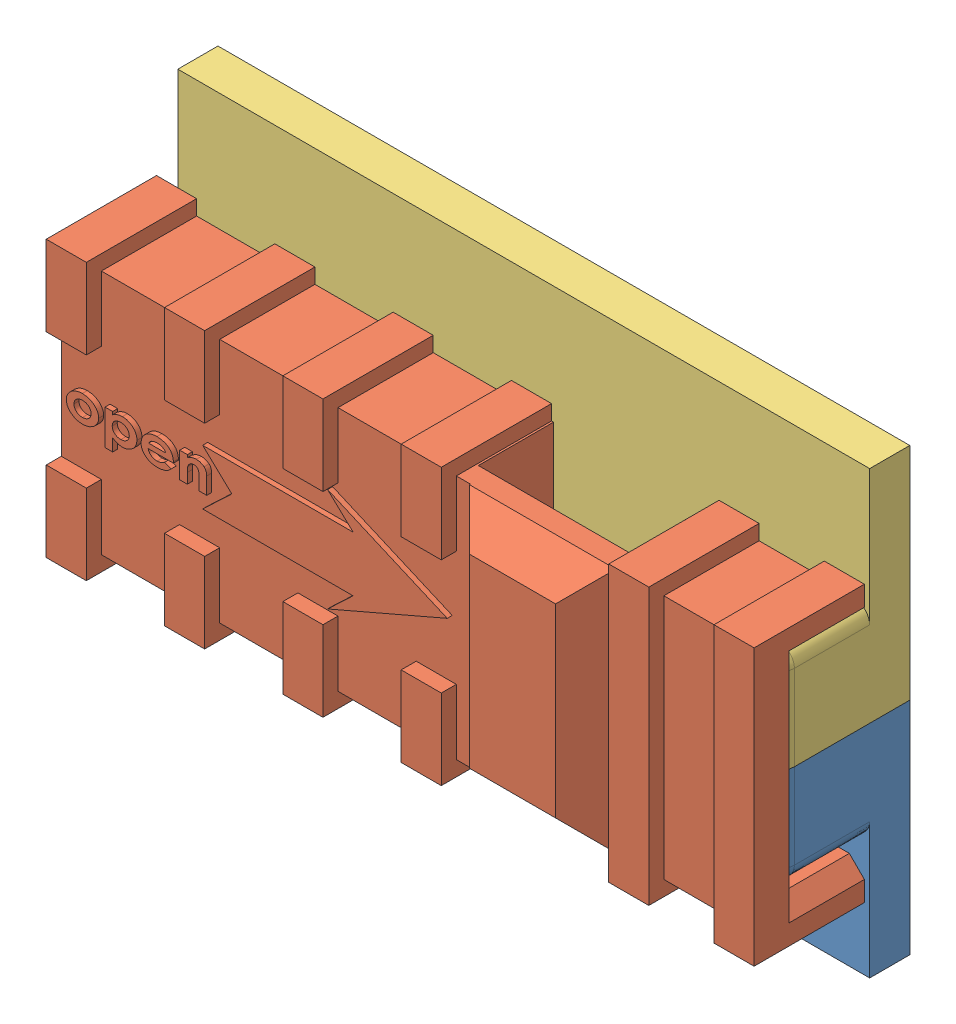
SolidWorks assembly Assem_Slider padlock, configuration Default. Lengths in mm.
Overall size (70.6 44 18.6).
3 component instances, 3 part files, 5 mates.
Components (placement in the parent):
- Slider of padlock for BOTTOM chamber-1: Slider of padlock for BOTTOM chamber [Default] at (19.2447 38.913 48.4256) x (-1 0 0) z (0 1 0) size (69 13.5 22)
- Padlock-1: Padlock [Default] at (12.4174 49.913 58.1756) size (70.6 27.5 12.9)
- Slider of padlock for top chamber-1: Slider of padlock for top chamber [Default] at (19.2447 60.913 48.4256) x (1 0 0) z (0 -1 0) size (69 13.5 22)
Mates (geometry in assembly coordinates):
- Coincident1: coincident anti-aligned: plane of Slider of padlock for BOTTOM chamber-1 through (-15.2553 49.913 47.4256) normal (0 1 0); plane of Slider of padlock for top chamber-1 through (53.7447 49.913 47.4256) normal (0 -1 0)
- Coincident2: coincident aligned: plane of Slider of padlock for BOTTOM chamber-1 through (53.7447 27.913 47.4256) normal (1 0 0); plane of Slider of padlock for top chamber-1 through (53.7447 71.913 47.4256) normal (1 0 0)
- Coincident3: coincident aligned: plane of Slider of padlock for BOTTOM chamber-1 through (19.2447 38.913 60.9256) normal (0 0 1); plane of Slider of padlock for top chamber-1 through (19.2447 60.913 60.9256) normal (0 0 1)
- Width1: width anti-aligned: plane of Padlock-1 through (40.2174 37.663 62.9256) normal (0 -1 0); plane of Padlock-1 through (40.2174 62.163 62.9256) normal (0 1 0); plane of Slider of padlock for top chamber-1 through (53.7447 59.913 60.9256) normal (0 1 0); plane of Slider of padlock for BOTTOM chamber-1 through (53.7447 39.913 60.9256) normal (0 -1 0)
- Coincident7: coincident anti-aligned: plane of Slider of padlock for BOTTOM chamber-1 through (19.2447 38.913 60.9256) normal (0 0 1); plane of Padlock-1 through (12.4174 49.913 60.9256) normal (0 0 -1)
